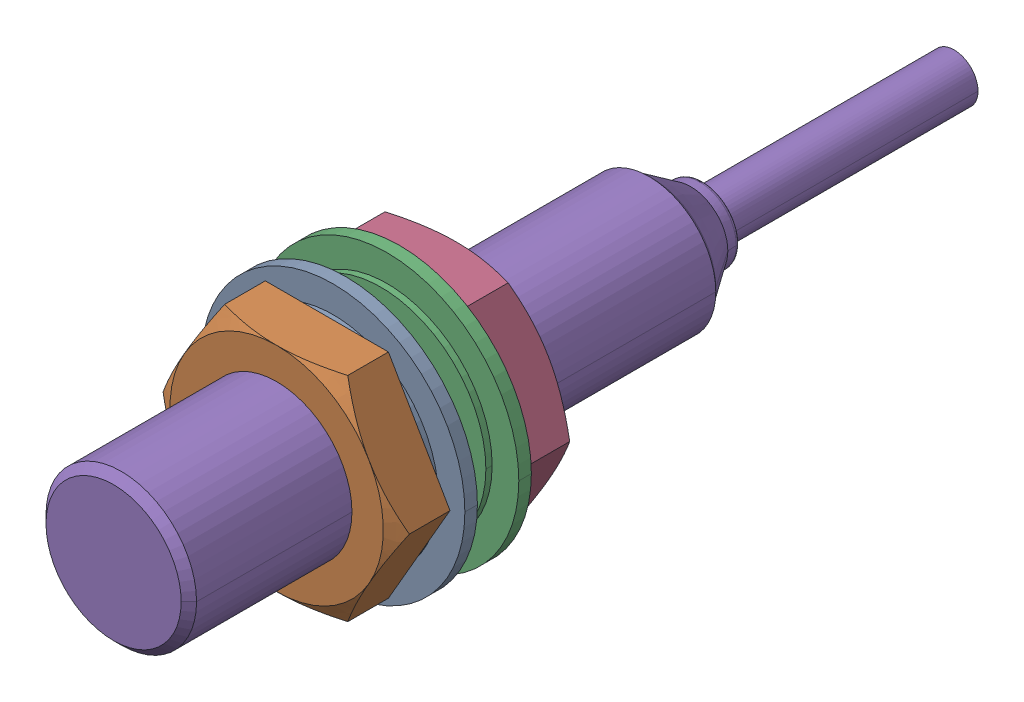
SolidWorks assembly 高型EMZ3_12S, configuration Default. Lengths in mm.
Overall size (21 21 67).
5 component instances, 3 part files, 0 mates.
Components (placement in the parent):
- 高型EMZ3_12S_3-1: 高型EMZ3_12S_3 [Default] at (0 0 -17) x (1 0 0) z (0 0 -1) size (21 21 2)
- 高型EMZ3_12S_5-1: 高型EMZ3_12S_5 [Default] at (0 0 -17) size (19.64 17.01 4.01)
- 高型EMZ3_12S_3-2: 高型EMZ3_12S_3 [Default] at (0 0 -23.3) size (21 21 2)
- 高型EMZ3_12S_5-2: 高型EMZ3_12S_5 [Default] at (0 0 -23.3) x (1 0 0) z (0 0 -1) size (19.64 17.01 4.01)
- 高型EMZ3_12S_9-1: 高型EMZ3_12S_9 [Default] at origin size (12 12 67)
